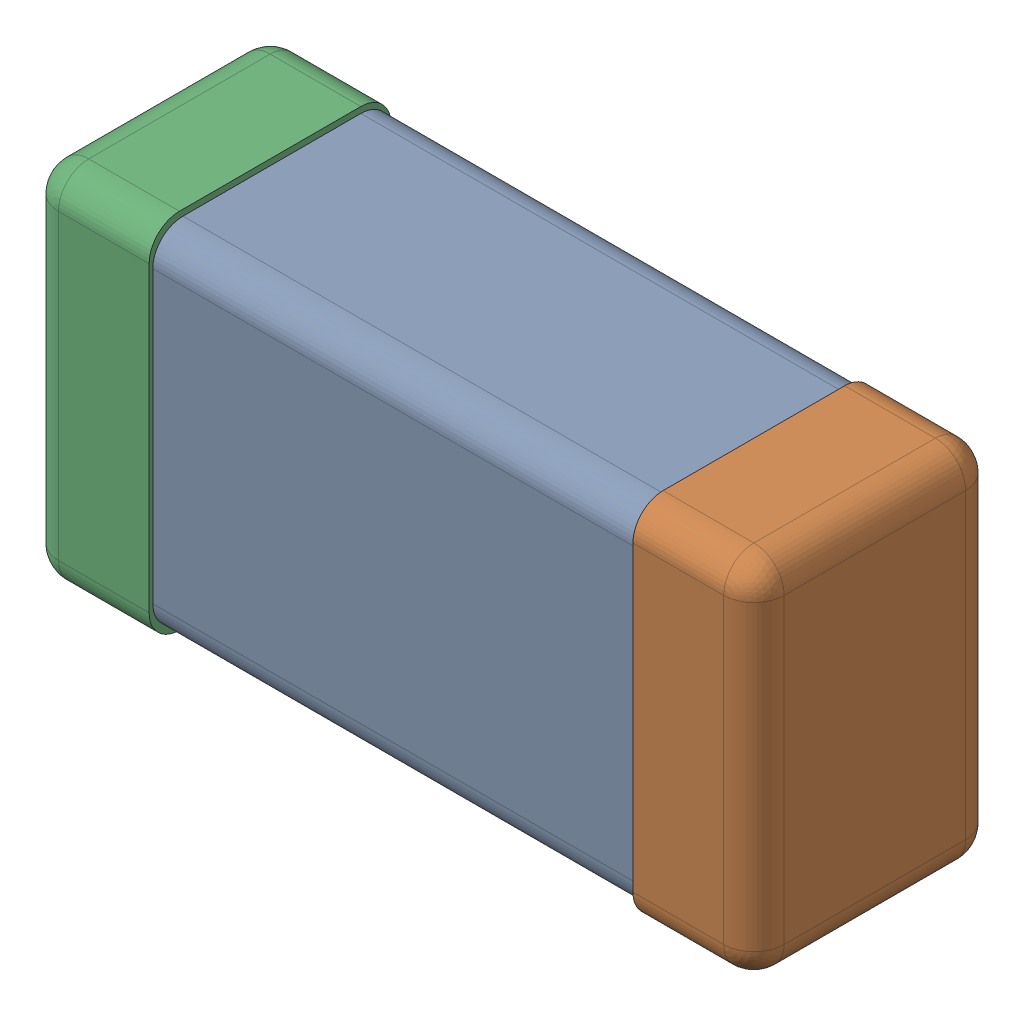
SolidWorks assembly C0201_020_26, configuration Standard. Lengths in mm.
Overall size (0.6 0.3 0.2).
4 component instances, 3 part files, 0 mates.
Components (placement in the parent):
- C0201_020_27-1: C0201_020_27 [Standard] at origin size (0.6 0.3 0.2)
  - Part 3_2-1: Part 3_2 [Standard] at (0 0 -7.3015) size (0.5 0.29 0.2)
  - Part 2_2-1: Part 2_2 [Standard] at (0 0 -7.3) size (0.1 0.3 0.2)
  - Part 1_2-1: Part 1_2 [Standard] at (0 0 -7.3) size (0.1 0.3 0.2)
